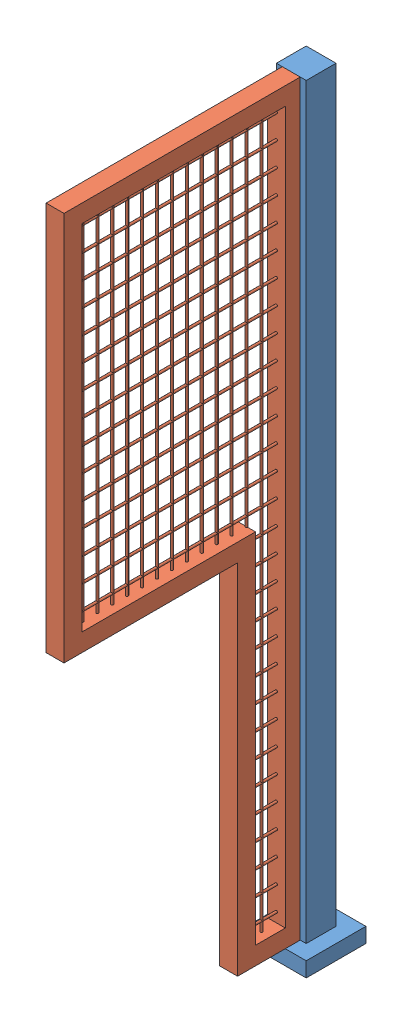
SolidWorks assembly Assieme1, configuration Default. Lengths in mm.
Overall size (200 2555 941.66).
9 component instances, 5 part files, 38 mates.
Components (placement in the parent):
- palo_barriera-2: palo_barriera [Default] at origin size (200 2555 200)
- palo_barriera-3: palo_barriera [Default] at (2000 0 0) size (200 2555 200) (hidden)
- palo_barriera-4: palo_barriera [Default] at (1100 0 0) size (200 2555 200) (hidden)
- Parte1^Assieme1-1: Parte1^Assieme1 [Default] at (1950 0 0) x (0 0 1) z (-1 0 0) size (200 2565 2102) (hidden, virtual)
- Parte2^Assieme1-1: Parte2^Assieme1 [Default] at (1950 2585 0) x (0 0 -1) z (0 -1 0) size (170 1090 2535) (hidden, virtual)
- palo_barriera-5: palo_barriera [Default] at (0 0 1300) size (200 2555 200) (hidden)
- rete1m_c-1: rete1m_c [Default] at (0 0 -700) size (60 2505 791.66)
- palo_barriera-6: palo_barriera [Default] at origin size (200 2555 200) (hidden)
- rete1m_c1-2: rete1m_c1 [Default] at (-1000 0 1300) x (0 0 -1) z (1 0 0) size (60 2505 455.28) (hidden)
Mates (geometry in assembly coordinates):
- Coincidente26: coincident aligned: plane of palo_barriera-2 through (0 2555 0) normal (0 1 0); plane of palo_barriera-3 through (2000 2555 0) normal (0 1 0)
- Coincidente27: coincident aligned: plane of palo_barriera-2 through (-50 2550 50) normal (0 0 1); plane of palo_barriera-3 through (1950 2550 50) normal (0 0 1)
- Distanza10: distance = 1900 mm anti-aligned: plane of palo_barriera-3 through (1950 2550 -50) normal (-1 0 0); plane of palo_barriera-2 through (50 2550 -50) normal (1 0 0)
- Coincidente29: coincident aligned: plane of palo_barriera-3 through (2000 0 -100) normal (0 0 -1); plane of palo_barriera-4 through (1100 0 -100) normal (0 0 -1)
- Coincidente30: coincident aligned: plane of palo_barriera-3 through (2000 2555 0) normal (0 1 0); plane of palo_barriera-4 through (1100 2555 0) normal (0 1 0)
- Distanza11: distance = 800 mm anti-aligned: plane of palo_barriera-4 through (1150 2550 -50) normal (1 0 0); plane of palo_barriera-3 through (1950 2550 -50) normal (-1 0 0)
- SulPosto1: in place: plane of ? through (3950 2550 1950) normal (-1 0 0); plane of ? through (3950 0 0) normal (-1 0 0); moOrthogonalPlaneRef_w of ? through (3950 2550 1950) normal (-1 0 0); plane of ? through (3950 0 0) normal (0 1 0); plane of ? through (3950 2550 1950) normal (-1 0 0); plane of ? through (3950 0 0) normal (0 0 1); plane of palo_barriera-3 through (1950 2550 -50) normal (-1 0 0); unknown of Parte1^Assieme1-1
- Coincidente32: coincident aligned: plane of palo_barriera-3; plane of Parte1^Assieme1-1
- Coincidente33: coincident aligned: moOrthogonalPlaneRef_w of palo_barriera-3 through (1950 0 0) normal (0 1 0); plane of Parte1^Assieme1-1 through (1950 0 0) normal (0 1 0)
- Coincidente34: coincident anti-aligned: moOrthogonalPlaneRef_w of palo_barriera-3 through (1950 0 0) normal (0 0 -1); plane of Parte1^Assieme1-1 through (1950 0 0) normal (0 0 1)
- SulPosto2: in place: plane of ? through (1741.1939 2585 1880) normal (0 -1 0); plane of ? through (0 2585 0) normal (0 -1 0); plane of ? through (1741.1939 2585 1880) normal (0 -1 0); plane of ? through (0 2585 0) normal (0 0 -1); plane of ? through (1741.1939 2585 1880) normal (0 -1 0); plane of ? through (0 2585 0) normal (-1 0 0); plane of Parte1^Assieme1-1 through (-258.8061 2585 -120) normal (0 -1 0); unknown of Parte2^Assieme1-1
- Coincidente35: coincident aligned: plane of Parte1^Assieme1-1; plane of Parte2^Assieme1-1
- Coincidente36: coincident aligned: moOrthogonalPlaneRef_w of Parte1^Assieme1-1 through (1950 2585 0) normal (1 0 0); plane of Parte2^Assieme1-1 through (1950 2585 0) normal (1 0 0)
- Coincidente37: coincident anti-aligned: moOrthogonalPlaneRef_w of Parte1^Assieme1-1 through (1950 2585 0) normal (0 0 1); plane of Parte2^Assieme1-1 through (1950 2585 0) normal (0 0 -1)
- Distanza16: distance = 1200 mm anti-aligned: plane of palo_barriera-5 through (-50 2550 1250) normal (0 0 -1); plane of palo_barriera-2 through (-50 2550 50) normal (0 0 1)
- Coincidente56: coincident aligned: plane of palo_barriera-2 through (-50 2550 -50) normal (-1 0 0); plane of palo_barriera-5 through (-50 2550 1250) normal (-1 0 0)
- Coincidente57: coincident aligned: plane of palo_barriera-2 through (0 0 100) normal (0 -1 0); plane of palo_barriera-5 through (0 0 1400) normal (0 -1 0)
- Coincidente64: coincident anti-aligned: plane of palo_barriera-2 through (-50 2550 50) normal (0 0 1); plane of rete1m_c-1 through (0 0 50) normal (0 0 -1)
- Distanza22: distance = 20 mm aligned: plane of rete1m_c-1 through (-30 110 50) normal (-1 0 0); plane of palo_barriera-2 through (-50 2550 -50) normal (-1 0 0)
- Coincidente66: coincident aligned: plane of palo_barriera-5 through (0 2555 1300) normal (0 1 0); plane of rete1m_c-1 through (30 2555 50) normal (0 1 0)
- Coincidente67: coordinate: point of palo_barriera-2
- Coincidente68: coincident anti-aligned: plane of palo_barriera-5 through (50 2550 1250) normal (1 0 0); plane of bariera_400mm-2 through (50 0 1300) normal (-1 0 0)
- Coincidente69: coincident aligned: plane of palo_barriera-5 through (0 2555 1300) normal (0 1 0); plane of bariera_400mm-2 through (450 2555 1300) normal (0 1 0)
- Distanza23: distance = 20 mm aligned: plane of bariera_400mm-2 through (50 50 1330) normal (0 0 1); plane of palo_barriera-5 through (-50 2550 1350) normal (0 0 1)
- Coincidente72: coincident anti-aligned: plane of palo_barriera-5 through (-50 2550 1250) normal (-1 0 0); plane of rete1m_c1-1 through (-50 0 1300) normal (1 0 0)
- Coincidente73: coincident aligned: plane of palo_barriera-5 through (0 2555 1300) normal (0 1 0); plane of rete1m_c1-1 through (-950 2555 1270) normal (0 1 0)
- Distanza24: distance = 20 mm aligned: plane of palo_barriera-5 through (-50 2550 1350) normal (0 0 1); plane of rete1m_c1-1 through (-950 110 1330) normal (0 0 1)
- SulPosto3: in place: plane of ? through (-900 2573.1025 1330) normal (1 0 0); plane of ? through (-900 0 0) normal (1 0 0); plane of ? through (-900 2573.1025 1330) normal (1 0 0); plane of ? through (-900 0 0) normal (0 1 0); plane of ? through (-900 2573.1025 1330) normal (1 0 0); plane of ? through (-900 0 0) normal (0 0 -1); plane of ? through (-900 2573.1025 1330) normal (1 0 0); unknown of ?
- Coincidente75: coincident aligned: plane of ?; plane of ?
- Coincidente76: coincident aligned: moOrthogonalPlaneRef_w of rete1m_c1-1 through (-900 0 1300) normal (0 1 0); plane of Parte3^Assieme1-1 through (-900 0 1300) normal (0 1 0)
- Coincidente77: coincident anti-aligned: moOrthogonalPlaneRef_w of rete1m_c1-1 through (-900 0 1300) normal (0 0 1); plane of Parte3^Assieme1-1 through (-900 0 1300) normal (0 0 -1)
- SulPosto4: in place: plane of rete1m_c-1 through (30 2555 50) normal (0 1 0); plane of ? through (0 2555 0) normal (0 1 0); plane of rete1m_c-1 through (30 2555 50) normal (0 1 0); plane of ? through (0 2555 0) normal (0 0 -1); plane of rete1m_c-1 through (30 2555 50) normal (0 1 0); plane of ? through (0 2555 0) normal (1 0 0); plane of rete1m_c-1 through (30 2555 50) normal (0 1 0); unknown of ?
- Coincidente78: coincident aligned: plane of ?; plane of ?
- Coincidente79: coincident aligned: moOrthogonalPlaneRef_w of rete1m_c-1 through (0 2555 -700) normal (0 0 -1); plane of Parte4^Assieme1-1 through (0 2555 -700) normal (0 0 -1)
- Coincidente80: coincident anti-aligned: moOrthogonalPlaneRef_w of rete1m_c-1 through (0 2555 -700) normal (-1 0 0); plane of Parte4^Assieme1-1 through (0 2555 -700) normal (1 0 0)
- Coincidente74: coincident anti-aligned: plane of palo_barriera-5 through (50 2550 1250) normal (1 0 0); plane of rete1m_c1-2 through (50 0 1300) normal (-1 0 0)
- Distanza25: distance = 20 mm aligned: plane of rete1m_c1-2 through (50 110 1330) normal (0 0 1); plane of palo_barriera-5 through (-50 2550 1350) normal (0 0 1)
- Coincidente76: coincident aligned: plane of palo_barriera-5 through (0 2555 1300) normal (0 1 0); plane of rete1m_c1-2 through (50 2555 1270) normal (0 1 0)
